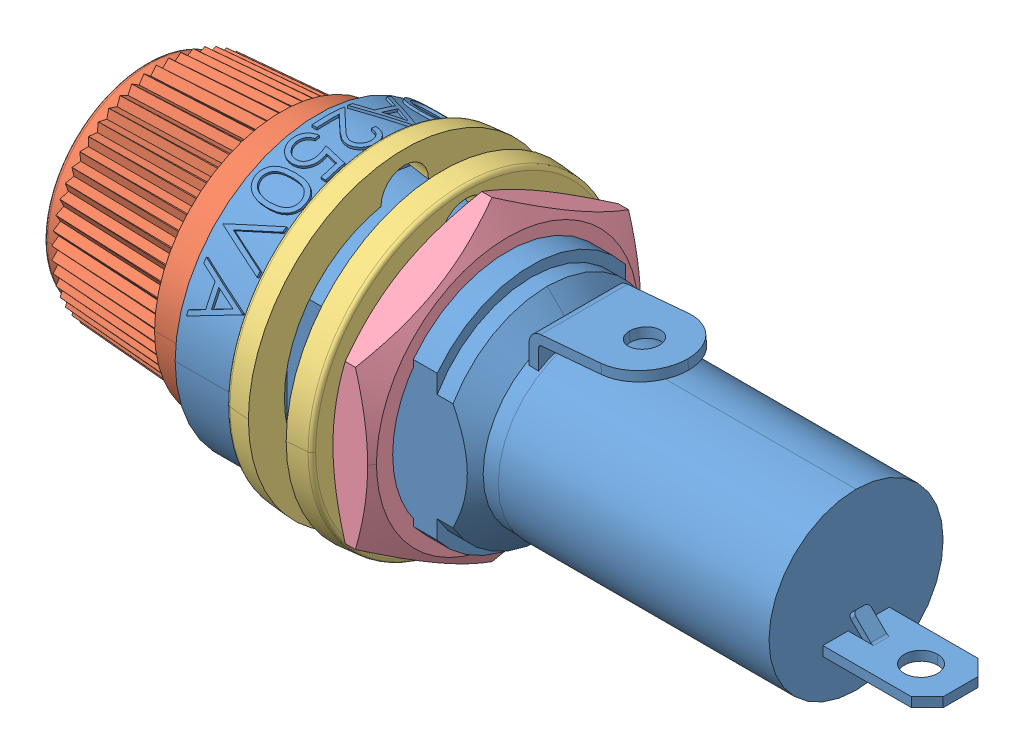
SolidWorks assembly SF372 10A 250VAC Fuse Holder, configuration Valor predeterminado. Lengths in mm.
Overall size (51.45 19.92 19.75).
6 component instances, 4 part files, 0 mates.
Components (placement in the parent):
- SF372 10A 250VAC Fuse Holder.STEP-1: SF372 10A 250VAC Fuse Holder.STEP [Valor predeterminado] at origin size (51.45 19.92 19.75)
  - SF372 - Body.STEP-1: SF372 - Body.STEP [Valor predeterminado] at origin size (40.6 18.15 18)
  - SF372 - Cap.STEP-1: SF372 - Cap.STEP [Valor predeterminado] at (1.2 0 0) size (16.25 16 16)
  - SF372 - Nylon Washer.STEP-1: SF372 - Nylon Washer.STEP [Valor predeterminado] at (5.5 0 0) x (-1 0 0) z (0 0 -1) size (1.5 19.75 19.75)
  - SF372 - Nylon Washer.STEP-2: SF372 - Nylon Washer.STEP [Valor predeterminado] at (7.8875 0 0) size (1.5 19.75 19.75)
  - SF372 - Nut.STEP-1: SF372 - Nut.STEP [Valor predeterminado] at (9.3875 0 0) size (2.6 19.92 17.26)
